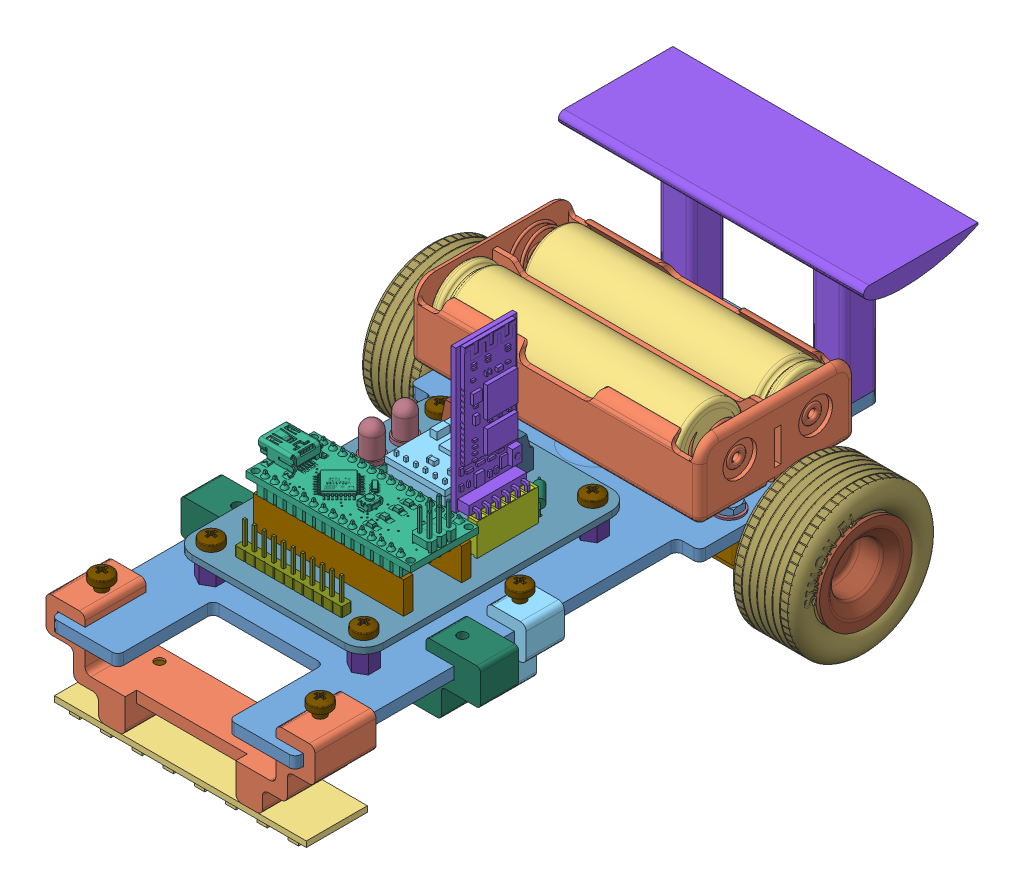
SolidWorks assembly LFR3_Assembly LFR3, configuration Default. Lengths in mm.
Overall size (115.21 79.64 171).
88 component instances, 41 part files, 32 mates.
Components (placement in the parent):
- Chassis-1: Chassis [Default] at (0 24.04 4) x (0 0 1) z (-1 0 0) size (160.5 8 76)
- Assembly batterijhouder-1: Assembly batterijhouder [Default] at (0 32.04 4) size (76 27.1 41.1)
  - Batterijhouder 2 x 18650-1: Batterijhouder 2 x 18650 [Default] x (1 0 0) z (0 1 0) size (76 41.1 19)
  - Batterij 2 x 18650-1: Batterij 2 x 18650 [Default] x (1 0 0) z (0 1 0) size (69.6 38.05 18.2)
  - countersunk flat head cross recess screw_iso-2: countersunk flat head cross recess screw_iso [ISO 7046-1 - M3 x 10 - Z - 10N] at (0 1.9 -9.925) x (0 -1 0) z (0 0 1) size (10 5.5 5.5)
  - countersunk flat head cross recess screw_iso-3: countersunk flat head cross recess screw_iso [ISO 7046-1 - M3 x 10 - Z - 10N] at (0 1.9 9.925) x (0 -1 0) z (-1 0 0) size (10 5.5 5.5)
- Assembly PCB-1: Assembly PCB [Default] at (0 33.04 64.5) size (50 58.6 70)
  - DRV8833-1: DRV8833 [Default] at (3 14 -9.5) x (0 0 1) z (-1 0 0) size (18.4 11.9 15.9)
  - Arduino Nano-1: Arduino Nano [Default] at (0.3598 23.6638 20.3801) x (-1 0 0) z (0 0 -1) size (44.95 20.74 17.81)
  - Header6P-1: Header6P [Default] at (9.35 1.6 -17.1) x (-1 0 0) z (0 1 0) size (16.1 2.4 11.5)
  - Header6P-2: Header6P [Default] at (9.35 1.6 -1.9) x (-1 0 0) z (0 1 0) size (16.1 2.4 11.5)
  - HC-05-2: HC-05 [Varsayılan] at (11.45 46.6 -1.45) x (0 -1 0) z (1 0 0) size (42.6 16.1 5.9)
  - Header6P-3: Header6P [Default] at (17 1.6 -3.15) x (0 0 -1) z (0 1 0) size (16.1 2.4 11.5)
  - Header15P-1: Header15P [Default] at (-15.76 2.4 4.86) x (-1 0 0) z (0 1 0) size (39.38 2.4 11.5)
  - Header15P-2: Header15P [Default] at (-15.76 2.4 20.0812) x (-1 0 0) z (0 1 0) size (39.38 2.4 11.5)
  - ScrewTerminal x 4-1: ScrewTerminal x 4 [Default] at (0 1.6 -26) x (-1 0 0) z (0 0 -1) size (10.62 12 6.3)
  - ScrewTerminal x 2-1: ScrewTerminal x 2 [Default] at (-10.48 1.6 -26) x (-1 0 0) z (0 0 -1) size (5.54 12 6.3)
  - Push button-1: Push button [Default] at (-18.25 1.6 -2.35) x (0 0 1) z (-1 0 0) size (7.14 7.7 6)
  - Led-1: Led [Default] at (-18.5 1.6 -19.33) x (0 0 1) z (-1 0 0) size (5.8 11.9 5.8)
  - PCB 50 x 70-3: PCB 50 x 70 [Default] at origin size (50 1.6 70)
  - Led-2: Led [Default] at (-18.5 1.6 -10.59) x (0 0 1) z (-1 0 0) size (5.8 11.9 5.8)
  - Weerstand-1: Weerstand [Default] at (-10.4645 1.6 -14.4645) x (0.707107 0 -0.707107) z (0.707107 0 0.707107) size (2.5 5.7 10.5)
  - Weerstand-2: Weerstand [Default] at (-10.4645 1.6 -5.9645) x (0.707107 0 -0.707107) z (0.707107 0 0.707107) size (2.5 5.7 10.5)
  - Weerstand-3: Weerstand [Default] at (13.0355 1.6 -22.9645) x (0.707107 0 -0.707107) z (0.707107 0 0.707107) size (2.5 5.7 10.5)
  - Header11P-1: Header11P [Default] at (0 1.6 28.5) size (27.94 11.74 2.54)
  - M3 spacer 6 mm-1: M3 spacer 6 mm [Default] at (20 -6 -30) size (5.6 12 6.47)
  - M3 spacer 6 mm-2: M3 spacer 6 mm [Default] at (-20 -6 -30) x (0.5 0 0.866025) z (-0.866025 0 0.5) size (5.6 12 6.47)
  - M3 spacer 6 mm-3: M3 spacer 6 mm [Default] at (-20 -6 30) x (0.5 0 0.866025) z (-0.866025 0 0.5) size (5.6 12 6.47)
  - M3 spacer 6 mm-4: M3 spacer 6 mm [Default] at (20 -6 30) size (5.6 12 6.47)
  - pan head cross recess screw_iso-1: pan head cross recess screw_iso [ISO 7045 - M3 x 5 - Z - 5N] at (20 4 30) x (0 -1 0) z (0 0 1) size (7.35 5.6 5.6)
  - pan head cross recess screw_iso-2: pan head cross recess screw_iso [ISO 7045 - M3 x 5 - Z - 5N] at (20 4 -30) x (0 -1 0) z (0 0 1) size (7.35 5.6 5.6)
  - pan head cross recess screw_iso-3: pan head cross recess screw_iso [ISO 7045 - M3 x 5 - Z - 5N] at (-20 4 30) x (0 -1 0) z (0 0 1) size (7.35 5.6 5.6)
  - pan head cross recess screw_iso-4: pan head cross recess screw_iso [ISO 7045 - M3 x 5 - Z - 5N] at (-20 4 -30) x (0 -1 0) z (0 0 1) size (7.35 5.6 5.6)
  - hex thin nut chamfered gradeab_iso-1: hex thin nut chamfered gradeab_iso [ISO - 4035 - M3 - N] at (20 -10.8 -30) x (1 0 0) z (0 -1 0) size (5.5 6.35 1.8)
  - hex thin nut chamfered gradeab_iso-2: hex thin nut chamfered gradeab_iso [ISO - 4035 - M3 - N] at (20 -10.8 30) x (1 0 0) z (0 -1 0) size (5.5 6.35 1.8)
  - hex thin nut chamfered gradeab_iso-3: hex thin nut chamfered gradeab_iso [ISO - 4035 - M3 - N] at (-20 -10.8 30) x (0.5 0 -0.866025) z (0 -1 0) size (5.5 6.35 1.8)
  - hex thin nut chamfered gradeab_iso-4: hex thin nut chamfered gradeab_iso [ISO - 4035 - M3 - N] at (-20 -10.8 -30) x (1 0 0) z (0 -1 0) size (5.5 6.35 1.8)
- Assembly schuiver QTR-8A-1: Assembly schuiver QTR-8A [Default] at (0 27.19 120) size (70.5 30.71 16)
  - QTR-8A schuiver-1: QTR-8A schuiver [Default] at (0 0 -13.425) size (70.5 22.5 16)
  - QTR-8A-1: QTR-8A [Default] at (0 -21 -5.425) x (1 0 0) z (0 0 -1) size (66 3.1 16)
  - Header11P90-1: Header11P90 [Default] at (-12.7 -22.46 -12.155) x (0 0 1) z (0 1 0) size (8.45 27.94 7.3)
  - pan head cross recess screw_iso-1: pan head cross recess screw_iso [ISO 7045 - M3 x 10 - Z - 10N] at (18 -23.4 -9.925) x (0 1 0) z (1 0 0) size (12.35 5.6 5.6)
  - pan head cross recess screw_iso-2: pan head cross recess screw_iso [ISO 7045 - M3 x 10 - Z - 10N] at (-18 -23.4 -9.925) x (0 1 0) z (1 0 0) size (12.35 5.6 5.6)
  - pan head cross recess screw_iso-3: pan head cross recess screw_iso [ISO 7045 - M3 x 5 - Z - 5N] at (-28.625 7.4 -5.425) x (0 -1 0) z (0 0 1) size (7.35 5.6 5.6)
  - pan head cross recess screw_iso-4: pan head cross recess screw_iso [ISO 7045 - M3 x 5 - Z - 5N] at (28.625 7.4 -5.425) x (0 -1 0) z (0 0 1) size (7.35 5.6 5.6)
- Assembly schuiver M3 ronde kop-1: Assembly schuiver M3 ronde kop [Default] at (0 27.19 62.2006) size (70.5 33.1 10)
  - M3 ronde kop schuiver-1: M3 ronde kop schuiver [Default] at (0 0 -5) size (70.5 20.75 10)
  - M3 ronde kop-1: M3 ronde kop [Default] at (0 -17.75 0) size (5.77 15 5)
  - pan head cross recess screw_iso-1: pan head cross recess screw_iso [ISO 7045 - M3 x 5 - Z - 5N] at (28.625 7.4 0) x (0 -1 0) z (0 0 1) size (7.35 5.6 5.6)
  - pan head cross recess screw_iso-2: pan head cross recess screw_iso [ISO 7045 - M3 x 5 - Z - 5N] at (-28.625 7.4 0) x (0 -1 0) z (0 0 1) size (7.35 5.6 5.6)
- KCD11-1: KCD11 [KCD11-A-101-O11XX] at (0 18.34 -26.25) size (15.06 19.01 10.5)
- Assembly spoiler-1: Assembly spoiler [Default] at (0 27.04 -31.5) size (80 45.35 30)
  - Spoiler-1: Spoiler [Default] at (0 40 0) x (1 0 0) z (0 0 -1) size (80 40 30)
  - pan head cross recess screw_iso-1: pan head cross recess screw_iso [ISO 7045 - M3 x 10 - Z - 10N] at (20 -5.4 0) x (0 1 0) z (-1 0 0) size (12.35 5.6 5.6)
  - pan head cross recess screw_iso-2: pan head cross recess screw_iso [ISO 7045 - M3 x 10 - Z - 10N] at (-20 -5.4 0) x (0 1 0) z (-1 0 0) size (12.35 5.6 5.6)
- Assembly wiel-1: Assembly wiel [Default] at (0 24.04 0) x (-1 0 0) z (0 0 -1) size (115.21 38 38)
  - Motor mount-1: Motor mount [Default] at origin size (76 12.7 29)
  - Micro Metal Gear Motor-1: Micro Metal Gear Motor [Default] at (29 -5.04 0) x (0 0 -1) z (1 0 0) size (12 10 35.9)
  - Micro Metal Gear Motor-2: Micro Metal Gear Motor [Default] at (-29 -5.04 0) x (0 0 1) z (-1 0 0) size (12 10 35.9)
  - Velg-1: Velg [Default] at (-48.6 -5.04 0) x (1 0 0) z (0 -1 0) size (17 24.25 24.25)
  - Velg-2: Velg [Default] at (48.6 -5.04 0) x (-1 0 0) z (0 -1 0) size (17 24.25 24.25)
  - Band-1: Band [Default] at (48.6 -5.04 0) x (1 0 0) z (0 1 0) size (18 38 38)
  - Band-2: Band [Default] at (-48.6 -5.04 0) x (-1 0 0) z (0 1 0) size (18 38 38)
  - hex thin nut chamfered gradeab_iso-1: hex thin nut chamfered gradeab_iso [ISO - 4035 - M3 - N] at (32.5 5.3 -11.25) x (0.5 0 0.866025) z (0 1 0) size (5.5 6.35 1.8)
  - hex thin nut chamfered gradeab_iso-2: hex thin nut chamfered gradeab_iso [ISO - 4035 - M3 - N] at (-32.5 5.3 11.25) x (0.5 0 -0.866025) z (0 1 0) size (5.5 6.35 1.8)
  - pan head cross recess screw_iso-1: pan head cross recess screw_iso [ISO 7045 - M3 x 10 - Z - 10N] at (32.5 -6.9 11.25) x (0 1 0) z (-1 0 0) size (12.35 5.6 5.6)
  - pan head cross recess screw_iso-2: pan head cross recess screw_iso [ISO 7045 - M3 x 10 - Z - 10N] at (32.5 -6.9 -11.25) x (0 1 0) z (-1 0 0) size (12.35 5.6 5.6)
  - pan head cross recess screw_iso-3: pan head cross recess screw_iso [ISO 7045 - M3 x 10 - Z - 10N] at (-32.5 -6.9 11.25) x (0 1 0) z (-1 0 0) size (12.35 5.6 5.6)
  - pan head cross recess screw_iso-4: pan head cross recess screw_iso [ISO 7045 - M3 x 10 - Z - 10N] at (-32.5 -6.9 -11.25) x (0 1 0) z (-1 0 0) size (12.35 5.6 5.6)
  - hex thin nut chamfered gradeab_iso-3: hex thin nut chamfered gradeab_iso [ISO - 4035 - M3 - N] at (-32.5 5.3 -11.25) x (-0.5 0 -0.866025) z (0 1 0) size (5.5 6.35 1.8)
  - hex thin nut chamfered gradeab_iso-4: hex thin nut chamfered gradeab_iso [ISO - 4035 - M3 - N] at (32.5 3.5 11.25) x (1 0 0) z (0 -1 0) size (5.5 6.35 1.8)
  - plain washer normal grade a_iso-1: plain washer normal grade a_iso [Washer ISO 7089 - 3] at (32.5 3 -11.25) x (0 -1 0) z (-1 0 0) size (0.5 7 7)
  - plain washer normal grade a_iso-2: plain washer normal grade a_iso [Washer ISO 7089 - 3] at (32.5 3 11.25) x (0 -1 0) z (-1 0 0) size (0.5 7 7)
  - plain washer normal grade a_iso-3: plain washer normal grade a_iso [Washer ISO 7089 - 3] at (-32.5 3 11.25) x (0 -1 0) z (-1 0 0) size (0.5 7 7)
  - plain washer normal grade a_iso-4: plain washer normal grade a_iso [Washer ISO 7089 - 3] at (-32.5 3 -11.25) x (0 -1 0) z (-1 0 0) size (0.5 7 7)
- Draaibaar neuswiel Rev 1.stp-1: Draaibaar neuswiel Rev 1.stp [Default] at (-16.6832 -12.8016 75.2942) x (-1 0 0) z (0 0 1) size (78.5 30.39 10) (hidden)
  - U-profiel.stp-1: U-profiel.stp [Default] at (-16.6832 -22.3016 -1.1116) size (10 8.5 8)
  - M3 Schuiver Rev A.stp-1: M3 Schuiver Rev A.stp [Default] at (-16.6832 -26.3016 2.8884) x (-1 0 0) z (0 0 1) size (78.5 16.89 10)
  - DIN 7991 - M3  x  16.stp-1: DIN 7991 - M3  x  16.stp [Default] at (-16.6832 -20.1916 2.8884) x (0 -1 0) z (-0.007352 0 0.999973) size (16 5.54 5.54)
  - Lager 683 ZZ.stp-1: Lager 683 ZZ.stp [Default] at (-16.6832 -16.3016 1.3884) x (0 0 -1) z (1 0 0) size (7 7 3)
  - DIN 934 - M2.stp-1: DIN 934 - M2.stp [Default] at (-21.6832 -16.3016 1.3884) x (-1 0 0) z (0 0 -1) size (1.6 4.62 4)
  - Lager 683 ZZ.stp-2: Lager 683 ZZ.stp [Default] at (-16.6832 -27.8016 2.8884) x (0.338716 0 -0.940889) z (0 1 0) size (7 7 3)
  - Lager 683 ZZ.stp-3: Lager 683 ZZ.stp [Default] at (-16.6832 -30.8016 2.8884) x (-0.000791 0 -1) z (0 1 0) size (7 7 3)
  - Draadstang M2.stp-1: Draadstang M2.stp [Default] at (-16.6832 -16.3016 1.3884) x (0 0 -1) z (1 0 0) size (2 2 12)
  - Bus diam 3 x 8.stp-1: Bus diam 3 x 8.stp [Default] at (-16.6832 -16.3016 1.3884) x (0 0 1) z (-1 0 0) size (3 3 8)
  - DIN 934 - M3.stp-1: DIN 934 - M3.stp [Default] at (-16.6832 -35.9016 2.8884) x (0 1 0) z (0 0 -1) size (2.4 6.35 5.5)
  - Bus diam 5 x 2.5.stp-1: Bus diam 5 x 2.5.stp [Default] at (-19.4332 -16.3016 1.3884) x (0 0 -1) z (1 0 0) size (4 4 2.5)
  - DIN 985 - M3.stp-1: DIN 985 - M3.stp [Default] at (-16.6832 -22.3016 2.8884) x (0 -1 0) z (0 0 1) size (4 6.35 5.5)
Mates (geometry in assembly coordinates):
- Coincident36: coincident anti-aligned: plane of Chassis-1 through (0 24.04 4) normal (-1 0 0)
- Coincident54: coincident anti-aligned: plane of Chassis-1 through (0 27.04 4) normal (0 1 0); plane of KCD11-1 through (-7.5 27.04 -21) normal (0 -1 0)
- Coincident55: coincident: point of Chassis-1; plane of KCD11-1 through (0 18.34 -26.25) normal (0 0 1)
- Coincident56: coincident aligned: plane of assembly through (0 0 0) normal (1 0 0); plane of KCD11-1 through (0 18.34 -26.25) normal (1 0 0)
- Concentric544: concentric anti-aligned: cylinder of Chassis-1 through (-20 32.04 34.5) axis (0 -1 0) radius 1.25; cylinder of Assembly PCB-1/M3 spacer 6 mm-2 through (-20 21.04 34.5) axis (0 1 0) radius 1.5
- Concentric545: concentric anti-aligned: cylinder of Chassis-1 through (20 32.04 94.5) axis (0 -1 0) radius 1.25; cylinder of Assembly PCB-1/M3 spacer 6 mm-4 through (20 21.04 94.5) axis (0 1 0) radius 1.5
- Coincident108: coincident anti-aligned: plane of Chassis-1 through (0 27.04 4) normal (0 1 0); plane of Assembly PCB-1/M3 spacer 6 mm-3 through (-20 27.04 94.5) normal (0 -1 0)
- Coincident110: coincident aligned: plane of Assembly schuiver QTR-8A-1 through (0 27.19 120) normal (1 0 0)
- Coincident111: coincident anti-aligned: plane of Chassis-1 through (0 24.04 4) normal (0 -1 0); plane of Assembly schuiver M3 ronde kop-1/M3 ronde kop schuiver-1 through (-32.25 24.04 67.2006) normal (0 1 0)
- Coincident112: coincident aligned: plane of Assembly schuiver M3 ronde kop-1 through (0 27.19 62.2006) normal (1 0 0)
- Concentric546: concentric anti-aligned: cylinder of Chassis-1 through (0 32.04 -5.925) axis (0 -1 0) radius 1.25; cylinder of Assembly batterijhouder-1/Batterijhouder 2 x 18650-1 through (0 -54.5126 -5.925) axis (0 1 0) radius 1.55
- Concentric547: concentric anti-aligned: cylinder of Chassis-1 through (0 32.04 13.925) axis (0 -1 0) radius 1.25; cylinder of Assembly batterijhouder-1/Batterijhouder 2 x 18650-1 through (0 -54.5126 13.925) axis (0 1 0) radius 1.55
- Coincident113: coincident anti-aligned: plane of Chassis-1 through (0 32.04 13.925) normal (0 1 0); plane of Assembly batterijhouder-1/Batterijhouder 2 x 18650-1 through (0 32.04 4) normal (0 -1 0)
- Concentric548: concentric aligned: cylinder of Chassis-1 through (-20 27.04 -31.5) axis (0 -1 0) radius 1.25; cylinder of Assembly spoiler-1/Spoiler-1 through (-20 37.04 -31.5) axis (0 -1 0) radius 1.25
- Concentric549: concentric aligned: cylinder of Chassis-1 through (20 27.04 -31.5) axis (0 -1 0) radius 1.25; cylinder of Assembly spoiler-1/Spoiler-1 through (20 37.04 -31.5) axis (0 -1 0) radius 1.25
- Coincident115: coincident anti-aligned: plane of Chassis-1 through (0 27.04 4) normal (0 1 0); plane of Assembly spoiler-1/Spoiler-1 through (0 27.04 -31.5) normal (0 -1 0)
- LimitDistance6: limit distance = 31.2006 mm: plane of Assembly schuiver M3 ronde kop-1/M3 ronde kop schuiver-1 through (0 27.19 57.2006) normal (0 0 -1); line of Chassis-1 through (-32 27.04 26) axis (0 -1 0)
- LimitDistance7: limit distance = 0 mm: plane of Assembly schuiver QTR-8A-1/QTR-8A schuiver-1 through (0 27.19 106.575) normal (0 0 -1); plane of Assembly schuiver M3 ronde kop-1/M3 ronde kop schuiver-1 through (0 27.19 67.2006) normal (0 0 1)
- Distance1: distance = 120 mm: unknown of Assembly schuiver QTR-8A-1/QTR-8A-1
- Coincident119: coincident anti-aligned: plane of Assembly wiel-1 through (0 24.04 0) normal (-1 0 0)
- Coincident120: coincident anti-aligned: plane of Assembly wiel-1 through (0 24.04 0) normal (0 1 0); plane of Chassis-1 through (0 24.04 4) normal (0 -1 0)
- Concentric552: concentric aligned: cylinder of Chassis-1 through (-32.5 32.04 -11.25) axis (0 -1 0) radius 1.25; cylinder of Assembly wiel-1/pan head cross recess screw_iso-1 through (-32.5 -8.26 -11.25) axis (0 -1 0) radius 1.5
- Tangent1: tangent anti-aligned: cylinder of Assembly wiel-1/Band-1 through (-48.6 19 0) axis (-1 0 0) radius 19
- Parallel6: parallel aligned: plane of Chassis-1 through (0 27.04 4) normal (0 1 0)
- Coincident123: coincident anti-aligned: plane of Assembly wiel-1 through (0 24.04 0) normal (0 0 -1)
- Coincident126: coincident anti-aligned: plane of Chassis-1 through (0 24.04 4) normal (0 -1 0); plane of Assembly schuiver QTR-8A-1/QTR-8A schuiver-1 through (-32.25 24.04 122.575) normal (0 1 0)
- Coincident127: coincident anti-aligned: plane of Chassis-1 through (0 24.04 4) normal (0 -1 0); plane of Assembly draaibaar neuswiel-1/Draaibaar neuswiel.stp-1/M3 Schuiver Rev A.stp-1 through (-25 24.04 90.6854) normal (0 1 0)
- Coincident130: coincident aligned: plane of Assembly draaibaar neuswiel-1 through (0 -11.8616 87.7971) normal (1 0 0)
- Coincident131: coincident aligned: plane of Chassis-1 through (0 24.04 4) normal (0 1 0); plane of Assembly draaibaar neuswiel-1/Draaibaar neuswiel.stp-1/M3 Schuiver Rev A.stp-1 through (-25 24.04 90.6854) normal (0 1 0)
- Coincident132: coincident anti-aligned: plane of Chassis-1 through (0 24.04 4) normal (0 -1 0); plane of Draaibaar neuswiel Rev 1.stp-1/M3 Schuiver Rev A.stp-1 through (-25 24.04 78.1826) normal (0 1 0)
- Parallel7: parallel aligned: plane of Chassis-1 through (-32 27.04 124.5) normal (0 0 1); plane of Draaibaar neuswiel Rev 1.stp-1/M3 Schuiver Rev A.stp-1 through (0 20.3739 83.1826) normal (0 0 1)
- Coincident134: coincident anti-aligned: plane of Draaibaar neuswiel Rev 1.stp-1/U-profiel.stp-1 through (0 9.5 74.1826) normal (-1 0 0)
